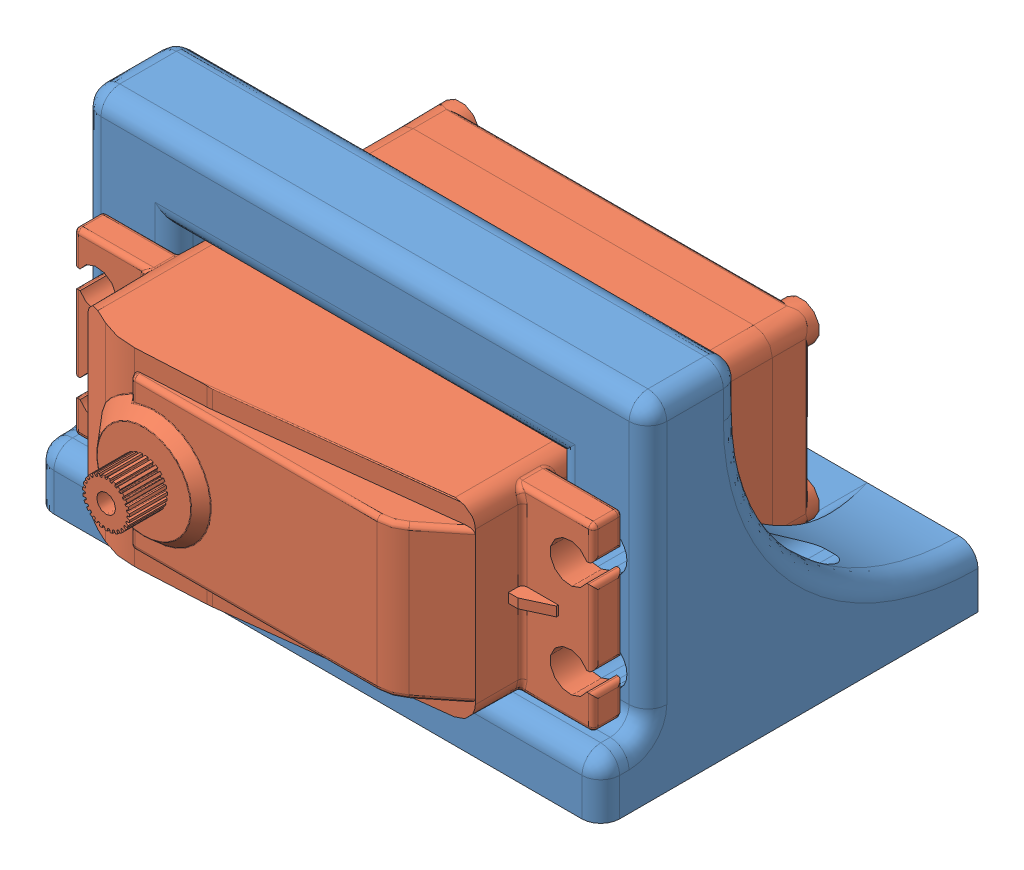
SolidWorks assembly Servo_Assembly, configuration Default. Lengths in mm.
Overall size (60 45 52.3).
2 component instances, 2 part files, 3 mates.
Components (placement in the parent):
- 20kg_Servo_Holder-1: 20kg_Servo_Holder [Default] at origin size (60 45 40)
- Servo 20kg-1: Servo 20kg [Default] at (29.8 15.05 -33.35) x (-1 0 0) z (0 1 0) size (55.1 45.65 20.12)
Mates (geometry in assembly coordinates):
- Coincident1: coincident anti-aligned: plane of 20kg_Servo_Holder-1 through (0 35 -5) normal (0 0 1); plane of Servo 20kg-1 through (54.85 20.05 -5) normal (0 0 -1)
- Coincident2: coincident anti-aligned: plane of 20kg_Servo_Holder-1 through (0 5 0) normal (0 1 0); plane of Servo 20kg-1 through (9.75 5 7.15) normal (0 -1 0)
- Coincident3: coincident anti-aligned: plane of 20kg_Servo_Holder-1 through (9.75 35 -5) normal (1 0 0); plane of Servo 20kg-1 through (9.75 25.1 7.15) normal (-1 0 0)
